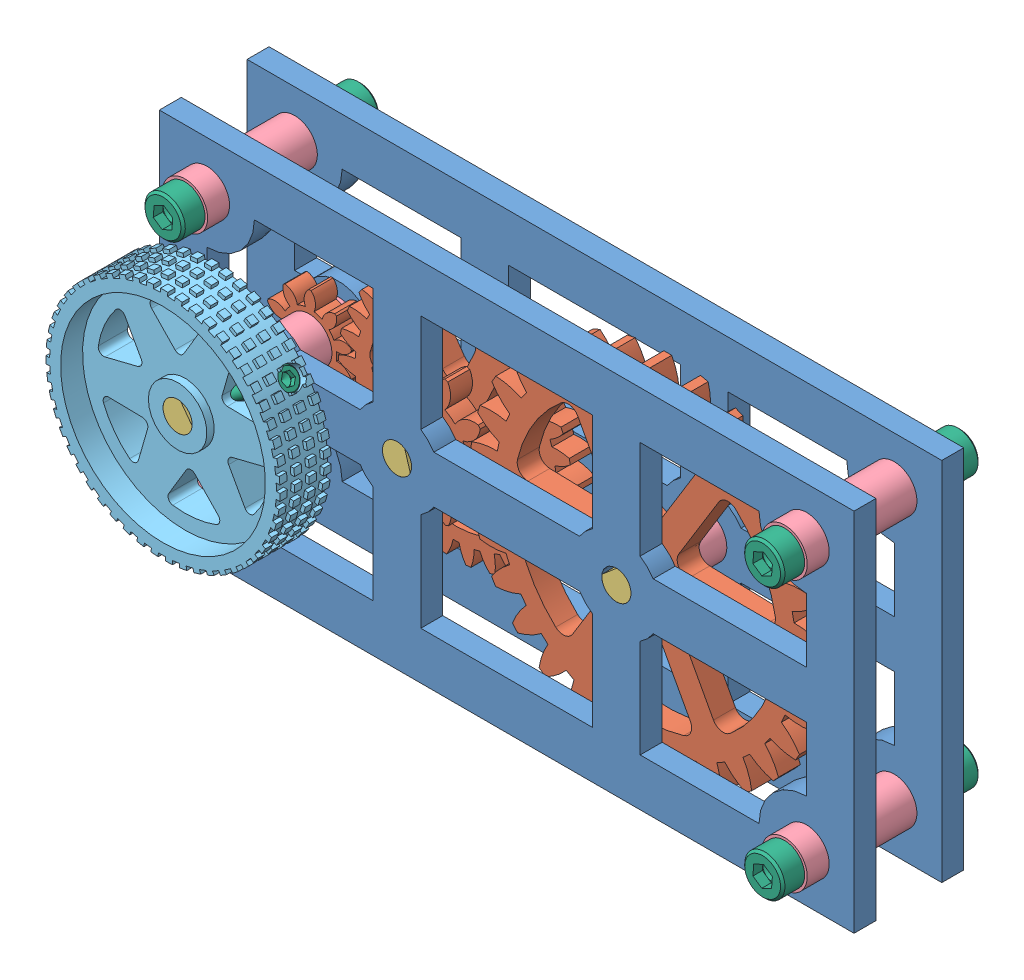
SolidWorks assembly GearBox, configuration Default. Lengths in mm.
Overall size (104.88 52.53 37).
41 component instances, 6 part files, 55 mates.
Components (placement in the parent):
- Part2-1: Part2 [Default] at (68.1213 57.8207 59.9782) size (95 50 3)
- SubAsmNum1-1: SubAsmNum1 [Default] at (25.918 57.2351 75.2799) x (0.325686 0.945478 0) z (0 0 -1) size (11.5 12 25)
  - root_gear.-1: root_gear. [10T 1.0 Mod] at (2.8997 6.6198 8.3017) size (11.5 12 3)
  - GearboxAxle-1: GearboxAxle [25mm] at (2.8997 6.6198 -9.6983) x (0.926974 -0.375125 0) z (0 0 1) size (4 3.98 25)
  - GearboxSpacer-1: GearboxSpacer [4.2mm ID] at (2.8997 6.6198 3.3017) x (0.851927 0.523661 0) z (0 0 1) size (6.2 6.2 5)
  - GearboxSpacer-2: GearboxSpacer [4.2 ID 1mm] at (2.8997 6.6198 12.3017) x (-0.923728 -0.383049 0) z (0 0 -1) size (6.2 6.2 1)
- SubAsmNum2-1: SubAsmNum2 [Default] at (36.0602 41.4959 43.3159) x (0.95277 -0.303694 0) z (0 0 1) size (31.89 32 15)
  - root_gear.-1: root_gear. [30T 1.0 Mod] at (11.2975 20.7352 20.6624) size (31.89 32 3)
  - root_gear.-2: root_gear. [10T 1.5 Mod] at (11.2975 20.7352 24.6624) size (17.25 18 3)
  - GearboxAxle-1: GearboxAxle [15mm] at (11.2975 20.7352 16.6624) x (0.926974 -0.375125 0) z (0 0 1) size (4 3.98 15)
  - GearboxSpacer-1: GearboxSpacer [4.2 ID 1mm] at (11.2975 20.7352 27.6624) x (0.999935 -0.011387 0) z (0 0 1) size (6.2 6.2 1)
  - GearboxSpacer-2: GearboxSpacer [4.2 ID 1mm] at (11.2975 20.7352 19.6624) size (6.2 6.2 1)
  - GearboxSpacer-3: GearboxSpacer [4.2 ID 1mm] at (11.2975 20.7352 23.6624) x (0.999999 0.001194 0) z (0 0 1) size (6.2 6.2 1)
- SubAsmNum3-1: SubAsmNum3 [Default] at (110.3273 37.315 35.3533) x (-0.103066 0.994675 0) z (0 0 1) size (47.84 48 25)
  - root_gear.-1: root_gear. [30T 1.5 Mod] at (23.2005 24.9477 32.625) size (47.84 48 3)
  - GearboxSpacer-1: GearboxSpacer [4.2 ID 1mm] at (23.2005 24.9477 36.625) x (-0.966667 -0.256037 0) z (0 0 -1) size (6.2 6.2 1)
  - GearboxSpacer-2: GearboxSpacer [4.2mm ID] at (23.2005 24.9477 27.625) x (-0.108036 0.994147 0) z (0 0 1) size (6.2 6.2 5)
  - GearboxAxle-2: GearboxAxle [25mm] at (23.2005 24.9477 14.625) x (0.926974 -0.375125 0) z (0 0 1) size (4 3.98 25)
- Part2-2: Part2 [Default] at (68.1213 57.8207 71.9782) size (95 50 3)
- GearboxSpacer-1: GearboxSpacer [2.85mm ID] at (109.1213 39.3207 62.9782) size (6.2 6.2 9)
- GearboxSpacer-2: GearboxSpacer [2.85mm ID] at (27.1213 76.3207 62.9782) size (6.2 6.2 9)
- GearboxSpacer-3: GearboxSpacer [2.85mm ID] at (109.1213 76.3207 62.9782) x (0.693232 0.720715 0) z (0 0 1) size (6.2 6.2 9)
- GearboxSpacer-4: GearboxSpacer [2.85mm ID] at (27.1213 39.3207 62.9782) size (6.2 6.2 9)
- GearboxSpacer-5: GearboxSpacer [3mm ID] at (109.1213 76.3207 77.9782) x (-0.923728 -0.383049 0) z (0 0 -1) size (6.2 6.2 3)
- GearboxSpacer-6: GearboxSpacer [3mm ID] at (109.1213 76.3207 56.9782) x (0.979577 0.201068 0) z (0 0 1) size (6.2 6.2 3)
- GearboxSpacer-7: GearboxSpacer [3mm ID] at (27.1213 39.3207 56.9782) x (0.948389 -0.317109 0) z (0 0 1) size (6.2 6.2 3)
- GearboxSpacer-8: GearboxSpacer [3mm ID] at (27.1213 76.3207 56.9782) x (0.999975 -0.007042 0) z (0 0 1) size (6.2 6.2 3)
- GearboxSpacer-9: GearboxSpacer [3mm ID] at (27.1213 76.3207 74.9782) x (0.921946 0.387318 0) z (0 0 1) size (6.2 6.2 3)
- GearboxSpacer-10: GearboxSpacer [3mm ID] at (109.1213 39.3207 56.9782) x (0.731523 0.681817 0) z (0 0 1) size (6.2 6.2 3)
- GearboxSpacer-11: GearboxSpacer [3mm ID] at (109.1213 39.3207 74.9782) size (6.2 6.2 3)
- GearboxSpacer-12: GearboxSpacer [3mm ID] at (27.1213 39.3207 74.9782) size (6.2 6.2 3)
- Knob-1: Knob [Default] at (33.1213 57.8207 79.9782) x (0 0 1) z (-0.594367 0.804194 0) size (7 32 32)
- socket head cap screw_am-2: socket head cap screw_am [B18.3.1M - 3 x 0.5 x 8 Hex SHCS -- 8NHX] at (27.1213 76.3207 80.9782) x (0 0 -1) z (-0.429644 0.902998 0) size (11 5.5 5.5)
- socket head cap screw_am-3: socket head cap screw_am [B18.3.1M - 3 x 0.5 x 8 Hex SHCS -- 8NHX] at (109.1213 76.3207 80.9782) x (0 0 -1) z (-0.429644 0.902998 0) size (11 5.5 5.5)
- socket head cap screw_am-4: socket head cap screw_am [B18.3.1M - 3 x 0.5 x 8 Hex SHCS -- 8NHX] at (109.1213 39.3207 53.9782) x (0 0 1) z (-0.050982 -0.9987 0) size (11 5.5 5.5)
- socket head cap screw_am-5: socket head cap screw_am [B18.3.1M - 3 x 0.5 x 8 Hex SHCS -- 8NHX] at (27.1213 39.3207 80.9782) x (0 0 -1) z (-0.429644 0.902998 0) size (11 5.5 5.5)
- socket head cap screw_am-6: socket head cap screw_am [B18.3.1M - 3 x 0.5 x 8 Hex SHCS -- 8NHX] at (27.1213 39.3207 53.9782) x (0 0 1) z (0.050982 0.9987 0) size (11 5.5 5.5)
- socket head cap screw_am-7: socket head cap screw_am [B18.3.1M - 3 x 0.5 x 8 Hex SHCS -- 8NHX] at (27.1213 76.3207 53.9782) x (0 0 1) z (-0.753472 -0.657479 0) size (11 5.5 5.5)
- socket head cap screw_am-8: socket head cap screw_am [B18.3.1M - 3 x 0.5 x 8 Hex SHCS -- 8NHX] at (109.1213 76.3207 53.9782) x (0 0 1) z (0.050982 0.9987 0) size (11 5.5 5.5)
- socket head cap screw_am-9: socket head cap screw_am [B18.3.1M - 3 x 0.5 x 8 Hex SHCS -- 8NHX] at (109.1213 39.3207 80.9782) x (0 0 -1) z (-0.429644 0.902998 0) size (11 5.5 5.5)
- socket head cap screw_am-10: socket head cap screw_am [B18.3.1M - 1.6 x 0.35 x 12 Hex SHCS -- 12NHX] at (45.2646 66.7957 81.9782) x (-0.804194 -0.594367 0) z (-0.189722 0.256698 -0.947688) size (13.6 3 3)
Mates (geometry in assembly coordinates):
- Concentric2: concentric anti-aligned: cylinder of Part2-1 through (53.1213 57.8207 59.9782) axis (0 0 1) radius 2; cylinder of SubAsmNum2-1/GearboxAxle-1 through (53.1213 57.8207 74.9782) axis (0 0 -1) radius 2
- Concentric3: concentric anti-aligned: cylinder of Part2-1 through (83.1213 57.8207 59.9782) axis (0 0 1) radius 2; cylinder of SubAsmNum3-1/GearboxAxle-2 through (83.1213 57.8207 74.9782) axis (0 0 -1) radius 2
- Coincident2: coincident anti-aligned: plane of Part2-1 through (68.1213 57.8207 62.9782) normal (0 0 1); plane of SubAsmNum3-1/GearboxSpacer-2 through (83.1213 57.8207 62.9782) normal (0 0 -1)
- Coincident3: coincident: line of Part2-1 through (115.6213 82.8207 62.9782) axis (-1 0 0); plane of SubAsmNum2-1/GearboxSpacer-2 through (53.1213 57.8207 62.9782) normal (0 0 -1)
- Concentric5: concentric aligned: cylinder of Part2-1 through (33.1213 57.8207 59.9782) axis (0 0 1) radius 2; cylinder of SubAsmNum1-1/GearboxAxle-1 through (33.1213 57.8207 59.9782) axis (0 0 1) radius 2
- Coincident5: coincident anti-aligned: plane of Part2-1 through (68.1213 57.8207 62.9782) normal (0 0 1); plane of SubAsmNum1-1/GearboxSpacer-2 through (33.1213 57.8207 62.9782) normal (0 0 -1)
- Concentric6: concentric aligned: cylinder of Part2-1 through (109.1213 76.3207 59.9782) axis (0 0 1) radius 1.5; circle of Part2-2
- Concentric7: concentric aligned: cylinder of Part2-1 through (27.1213 76.3207 59.9782) axis (0 0 1) radius 1.5; cylinder of Part2-2 through (27.1213 76.3207 71.9782) axis (0 0 1) radius 1.5
- Concentric8: concentric aligned: cylinder of Part2-1 through (109.1213 76.3207 59.9782) axis (0 0 1) radius 1.5; circle of GearboxSpacer-3
- Coincident8: coincident anti-aligned: plane of Part2-1 through (68.1213 57.8207 62.9782) normal (0 0 1); plane of GearboxSpacer-3 through (109.1213 76.3207 62.9782) normal (0 0 -1)
- Concentric9: concentric anti-aligned: circle of Part2-1; circle of GearboxSpacer-1
- Coincident9: coincident anti-aligned: plane of Part2-1 through (68.1213 57.8207 62.9782) normal (0 0 1); plane of GearboxSpacer-1 through (109.1213 39.3207 62.9782) normal (0 0 -1)
- Concentric10: concentric anti-aligned: cylinder of Part2-1 through (27.1213 76.3207 59.9782) axis (0 0 1) radius 1.5; cylinder of GearboxSpacer-2 through (27.1213 76.3207 71.9782) axis (0 0 -1) radius 1.425
- Coincident10: coincident anti-aligned: plane of Part2-1 through (68.1213 57.8207 62.9782) normal (0 0 1); plane of GearboxSpacer-2 through (27.1213 76.3207 62.9782) normal (0 0 -1)
- Concentric11: concentric anti-aligned: cylinder of Part2-1 through (27.1213 39.3207 59.9782) axis (0 0 1) radius 1.5; cylinder of GearboxSpacer-4 through (27.1213 39.3207 71.9782) axis (0 0 -1) radius 1.425
- Coincident11: coincident anti-aligned: plane of Part2-1 through (68.1213 57.8207 62.9782) normal (0 0 1); plane of GearboxSpacer-4 through (27.1213 39.3207 62.9782) normal (0 0 -1)
- Coincident12: coincident anti-aligned: plane of Part2-2 through (68.1213 57.8207 71.9782) normal (0 0 -1); plane of GearboxSpacer-3 through (109.1213 76.3207 71.9782) normal (0 0 1)
- Coincident13: coincident anti-aligned: plane of Part2-2 through (68.1213 57.8207 74.9782) normal (0 0 1); plane of GearboxSpacer-5 through (109.1213 76.3207 74.9782) normal (0 0 -1)
- Concentric13: concentric aligned: cylinder of Part2-2 through (109.1213 76.3207 71.9782) axis (0 0 1) radius 1.5; cylinder of GearboxSpacer-5 through (109.1213 76.3207 74.9782) axis (0 0 1) radius 1.5
- Concentric14: concentric anti-aligned: cylinder of Part2-1 through (109.1213 76.3207 59.9782) axis (0 0 1) radius 1.5; cylinder of GearboxSpacer-6 through (109.1213 76.3207 59.9782) axis (0 0 -1) radius 1.5
- Coincident14: coincident anti-aligned: plane of Part2-1 through (68.1213 57.8207 59.9782) normal (0 0 -1); plane of GearboxSpacer-6 through (109.1213 76.3207 59.9782) normal (0 0 1)
- Concentric15: concentric anti-aligned: cylinder of Part2-1 through (109.1213 39.3207 59.9782) axis (0 0 1) radius 1.5; cylinder of GearboxSpacer-10 through (109.1213 39.3207 59.9782) axis (0 0 -1) radius 1.5
- Coincident16: coincident anti-aligned: plane of Part2-1 through (68.1213 57.8207 59.9782) normal (0 0 -1); plane of GearboxSpacer-10 through (109.1213 39.3207 59.9782) normal (0 0 1)
- Coincident17: coincident anti-aligned: plane of Part2-2 through (68.1213 57.8207 74.9782) normal (0 0 1); plane of GearboxSpacer-11 through (109.1213 39.3207 74.9782) normal (0 0 -1)
- Concentric16: concentric anti-aligned: cylinder of Part2-2 through (109.1213 39.3207 71.9782) axis (0 0 1) radius 1.5; cylinder of GearboxSpacer-11 through (109.1213 39.3207 77.9782) axis (0 0 -1) radius 1.5
- Coincident18: coincident anti-aligned: plane of Part2-1 through (68.1213 57.8207 59.9782) normal (0 0 -1); plane of GearboxSpacer-8 through (27.1213 76.3207 59.9782) normal (0 0 1)
- Concentric17: concentric anti-aligned: cylinder of Part2-1 through (27.1213 76.3207 59.9782) axis (0 0 1) radius 1.5; cylinder of GearboxSpacer-8 through (27.1213 76.3207 59.9782) axis (0 0 -1) radius 1.5
- Coincident19: coincident aligned: cylinder of Part2-1 through (27.1213 39.3207 59.9782) axis (0 0 1) radius 1.5; circle of GearboxSpacer-7
- Coincident20: coincident anti-aligned: plane of Part2-1 through (68.1213 57.8207 59.9782) normal (0 0 -1); plane of GearboxSpacer-7 through (27.1213 39.3207 59.9782) normal (0 0 1)
- Concentric18: concentric anti-aligned: cylinder of Part2-2 through (27.1213 76.3207 71.9782) axis (0 0 1) radius 1.5; cylinder of GearboxSpacer-9 through (27.1213 76.3207 77.9782) axis (0 0 -1) radius 1.5
- Coincident21: coincident anti-aligned: plane of Part2-2 through (68.1213 57.8207 74.9782) normal (0 0 1); plane of GearboxSpacer-9 through (27.1213 76.3207 74.9782) normal (0 0 -1)
- Coincident22: coincident anti-aligned: plane of Part2-2 through (68.1213 57.8207 74.9782) normal (0 0 1); plane of GearboxSpacer-12 through (27.1213 39.3207 74.9782) normal (0 0 -1)
- Concentric19: concentric anti-aligned: cylinder of Part2-2 through (27.1213 39.3207 71.9782) axis (0 0 1) radius 1.5; cylinder of GearboxSpacer-12 through (27.1213 39.3207 77.9782) axis (0 0 -1) radius 1.5
- Concentric20: concentric anti-aligned: cylinder of SubAsmNum1-1/GearboxAxle-1 through (33.1213 57.8207 59.9782) axis (0 0 1) radius 2; cylinder of Knob-1 through (33.1213 57.8207 79.9782) axis (0 0 -1) radius 2
- Coincident23: coincident aligned: plane of SubAsmNum1-1/GearboxAxle-1 through (33.1213 57.8207 84.9782) normal (0 0 1); plane of Knob-1 through (34.7296 59.0095 84.9782) normal (0 0 1)
- Concentric21: concentric anti-aligned: cylinder of GearboxSpacer-9 through (27.1213 76.3207 77.9782) axis (0 0 -1) radius 1.5; cylinder of socket head cap screw_am-2 through (27.1213 76.3207 112.7282) axis (0 0 1) radius 1.5
- Coincident24: coincident anti-aligned: plane of GearboxSpacer-9 through (27.1213 76.3207 77.9782) normal (0 0 1); plane of socket head cap screw_am-2 through (24.638 75.1392 77.9782) normal (0 0 -1)
- Concentric22: concentric aligned: cylinder of GearboxSpacer-8 through (27.1213 76.3207 59.9782) axis (0 0 -1) radius 1.5; cylinder of socket head cap screw_am-7 through (27.1213 76.3207 22.2282) axis (0 0 -1) radius 1.5
- Coincident25: coincident anti-aligned: plane of GearboxSpacer-8 through (27.1213 76.3207 56.9782) normal (0 0 -1); plane of socket head cap screw_am-7 through (25.3132 78.3928 56.9782) normal (0 0 1)
- Coincident26: coincident anti-aligned: plane of GearboxSpacer-7 through (27.1213 39.3207 56.9782) normal (0 0 -1); plane of socket head cap screw_am-6 through (29.8677 39.1805 56.9782) normal (0 0 1)
- Concentric23: concentric aligned: cylinder of GearboxSpacer-7 through (27.1213 39.3207 59.9782) axis (0 0 -1) radius 1.5; cylinder of socket head cap screw_am-6 through (27.1213 39.3207 22.2282) axis (0 0 -1) radius 1.5
- Coincident27: coincident anti-aligned: plane of GearboxSpacer-12 through (27.1213 39.3207 77.9782) normal (0 0 1); plane of socket head cap screw_am-5 through (24.638 38.1392 77.9782) normal (0 0 -1)
- Concentric24: concentric anti-aligned: cylinder of GearboxSpacer-12 through (27.1213 39.3207 77.9782) axis (0 0 -1) radius 1.5; cylinder of socket head cap screw_am-5 through (27.1213 39.3207 112.7282) axis (0 0 1) radius 1.5
- Coincident28: coincident anti-aligned: plane of GearboxSpacer-5 through (109.1213 76.3207 77.9782) normal (0 0 1); plane of socket head cap screw_am-3 through (106.638 75.1392 77.9782) normal (0 0 -1)
- Coincident29: coincident anti-aligned: plane of GearboxSpacer-11 through (109.1213 39.3207 77.9782) normal (0 0 1); plane of socket head cap screw_am-9 through (106.638 38.1392 77.9782) normal (0 0 -1)
- Concentric25: concentric aligned: cylinder of GearboxSpacer-5 through (109.1213 76.3207 74.9782) axis (0 0 1) radius 1.5; cylinder of socket head cap screw_am-3 through (109.1213 76.3207 112.7282) axis (0 0 1) radius 1.5
- Concentric26: concentric anti-aligned: cylinder of GearboxSpacer-11 through (109.1213 39.3207 77.9782) axis (0 0 -1) radius 1.5; cylinder of socket head cap screw_am-9 through (109.1213 39.3207 112.7282) axis (0 0 1) radius 1.5
- Coincident30: coincident anti-aligned: plane of GearboxSpacer-6 through (109.1213 76.3207 56.9782) normal (0 0 -1); plane of socket head cap screw_am-8 through (111.8677 76.1805 56.9782) normal (0 0 1)
- Concentric27: concentric aligned: cylinder of GearboxSpacer-6 through (109.1213 76.3207 59.9782) axis (0 0 -1) radius 1.5; cylinder of socket head cap screw_am-8 through (109.1213 76.3207 22.2282) axis (0 0 -1) radius 1.5
- Concentric28: concentric aligned: cylinder of GearboxSpacer-10 through (109.1213 39.3207 59.9782) axis (0 0 -1) radius 1.5; cylinder of socket head cap screw_am-4 through (109.1213 39.3207 22.2282) axis (0 0 -1) radius 1.5
- Coincident32: coincident aligned: circle of GearboxSpacer-10; plane of socket head cap screw_am-4 through (106.3748 39.4609 56.9782) normal (0 0 1)
- Coincident34: coincident anti-aligned: plane of SubAsmNum1-1/GearboxAxle-1 through (35.1138 57.6484 59.9782) normal (0.804194 0.594367 0); plane of socket head cap screw_am-10 through (33.989 59.1703 82.1701) normal (-0.804194 -0.594367 0)
- Concentric32: concentric anti-aligned: cylinder of Knob-1 through (33.1213 57.8207 81.9782) axis (-0.804194 -0.594367 0) radius 1.5; cylinder of socket head cap screw_am-10 through (70.7977 85.6668 81.9782) axis (0.804194 0.594367 0) radius 0.8
- GearMate5: gear = 1 : 3 mm: axis of SubAsmNum2-1/GearboxAxle-1 through (53.1213 57.8207 74.9782) axis (0 0 -1); line of SubAsmNum1-1/GearboxAxle-1 through (33.1213 57.8207 59.9782) axis (0 0 1)
- GearMate8: gear = 3 : 1 mm: line of SubAsmNum2-1/GearboxSpacer-1 through (53.1213 57.8207 71.9782) axis (0 0 -1); line of SubAsmNum3-1/GearboxSpacer-2 through (83.1213 57.8207 67.9782) axis (0 0 -1)
